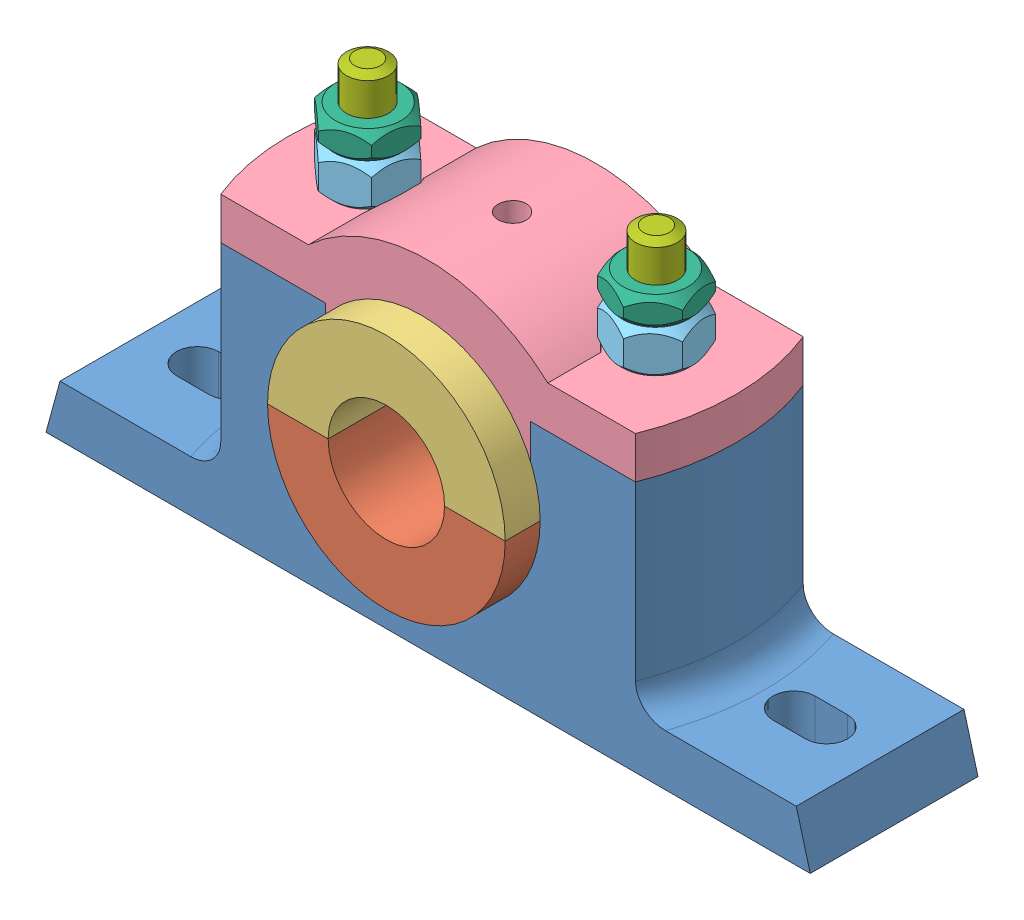
SolidWorks assembly Assem2, configuration Default. Lengths in mm.
Overall size (164 86 51).
10 component instances, 7 part files, 17 mates.
Components (placement in the parent):
- Part1-1: Part1 [Default] at (72.6905 62.3601 135.6077) size (164 54 36)
- part5-1: part5 [Default] at (72.6905 100.3601 111.5678) x (0 0 1) z (-1 0 0) size (51 25.5 51)
- part4-1: part4 [Default] at (72.6905 100.3601 162.5678) x (0 0 -1) z (-1 0 0) size (51 25.5 51)
- Part2-1: Part2 [Default] at (72.6905 97.3601 135.6077) size (96 32 36)
- Part6.1-1: Part6.1 [Default] at (41.6905 129.8601 135.6077) x (0.946515 0 -0.322661) z (0.322661 0 0.946515) size (19.8 9 15.59)
- Part7.1-1: Part7.1 [Default] at (41.6905 137.3601 135.6077) x (0.193825 0 -0.981036) z (0.981036 0 0.193825) size (19.8 6 15.59)
- Part3.1-1: Part3.1 [Default] at (41.6905 67.3601 135.6077) x (-1 0 0) z (0 1 0) size (19 19 84)
- Part3.1-2: Part3.1 [Default] at (103.6905 67.3601 135.6077) x (-1 0 0) z (0 1 0) size (19 19 84)
- Part7.1-2: Part7.1 [Default] at (103.6905 137.3601 135.6077) x (-0.193825 0 -0.981036) z (-0.981036 0 0.193825) size (19.8 6 15.59)
- Part6.1-2: Part6.1 [Default] at (103.6905 129.8601 135.6077) x (-0.946515 0 -0.322661) z (-0.322661 0 0.946515) size (19.8 9 15.59)
Mates (geometry in assembly coordinates):
- Coincident1: coincident aligned: cylinder of Part1-1 through (72.6905 81.3601 137.0678) axis (0 1 0) radius 3; circle of part5-1
- Parallel1: parallel anti-aligned: plane of Part1-1 through (72.6905 100.3601 153.6077) normal (0 0 1); plane of part5-1 through (85.1905 100.3601 111.5678) normal (0 0 -1)
- Concentric1: concentric aligned: cylinder of Part1-1 through (72.6905 100.3601 153.6077) axis (0 0 -1) radius 19; cylinder of part5-1 through (72.6905 100.3601 111.5678) axis (0 0 -1) radius 17.5
- Concentric3: concentric anti-aligned: cylinder of part5-1 through (72.6905 100.3601 111.5678) axis (0 0 -1) radius 12.5; cylinder of part4-1 through (72.6905 100.3601 162.5678) axis (0 0 1) radius 12.5
- Coincident9: coincident anti-aligned: plane of part5-1 through (72.6905 100.3601 111.5678) normal (0 1 0); plane of part4-1 through (72.6905 100.3601 162.5678) normal (0 -1 0)
- Coincident10: coincident aligned: plane of part5-1 through (85.1905 100.3601 162.5678) normal (0 0 1); plane of part4-1 through (85.1905 100.3601 162.5678) normal (0 0 1)
- Concentric4: concentric anti-aligned: cylinder of Part1-1 through (41.6905 70.3601 135.6077) axis (0 -1 0) radius 4.5; cylinder of Part2-1 through (41.6905 125.3601 135.6077) axis (0 1 0) radius 4.5
- Coincident11: coincident anti-aligned: plane of Part1-1 through (22.6905 116.3601 153.6077) normal (0 1 0); plane of Part2-1 through (50.6905 116.3601 153.6077) normal (0 -1 0)
- Coincident13: coincident anti-aligned: plane of Part1-1 through (72.6905 70.3601 135.6077) normal (0 -1 0); plane of Part3.1-1 through (41.6905 70.3601 135.6077) normal (0 1 0)
- Concentric6: concentric aligned: cylinder of Part1-1 through (41.6905 70.3601 135.6077) axis (0 -1 0) radius 4.5; cylinder of Part3.1-1 through (41.6905 148.3601 135.6077) axis (0 -1 0) radius 4.5
- Concentric7: concentric aligned: cylinder of Part6.1-1 through (41.6905 134.3601 135.6077) axis (0 -1 0) radius 4.5; cylinder of Part3.1-1 through (41.6905 148.3601 135.6077) axis (0 -1 0) radius 4.5
- Coincident14: coincident anti-aligned: plane of Part2-1 through (22.6905 125.3601 153.6077) normal (0 1 0); plane of Part6.1-1 through (41.6905 125.3601 135.6077) normal (0 -1 0)
- Concentric8: concentric aligned: cylinder of Part7.1-1 through (41.6905 140.3601 135.6077) axis (0 -1 0) radius 4.5; cylinder of Part3.1-1 through (41.6905 148.3601 135.6077) axis (0 -1 0) radius 4.5
- Coincident15: coincident anti-aligned: plane of Part6.1-1 through (41.6905 134.3601 135.6077) normal (0 1 0); plane of Part7.1-1 through (41.6905 134.3601 135.6077) normal (0 -1 0)
- Coincident16: coincident aligned: plane of Part1-1 through (72.6905 100.3601 153.6077) normal (0 0 1); plane of Part2-1 through (72.6905 97.3601 153.6077) normal (0 0 1)
- Parallel2: parallel anti-aligned: plane of Part1-1 through (51.6905 70.3601 145.6077) normal (-1 0 0); plane of Part3.1-1 through (51.1905 70.3601 145.1077) normal (1 0 0)
- Parallel3: parallel aligned: plane of Part6.1-1 through (33.1718 134.3601 138.5116) normal (-0.658375 0 0.75269); plane of Part7.1-1 through (33.1718 140.3601 138.5116) normal (-0.658375 0 0.75269)
